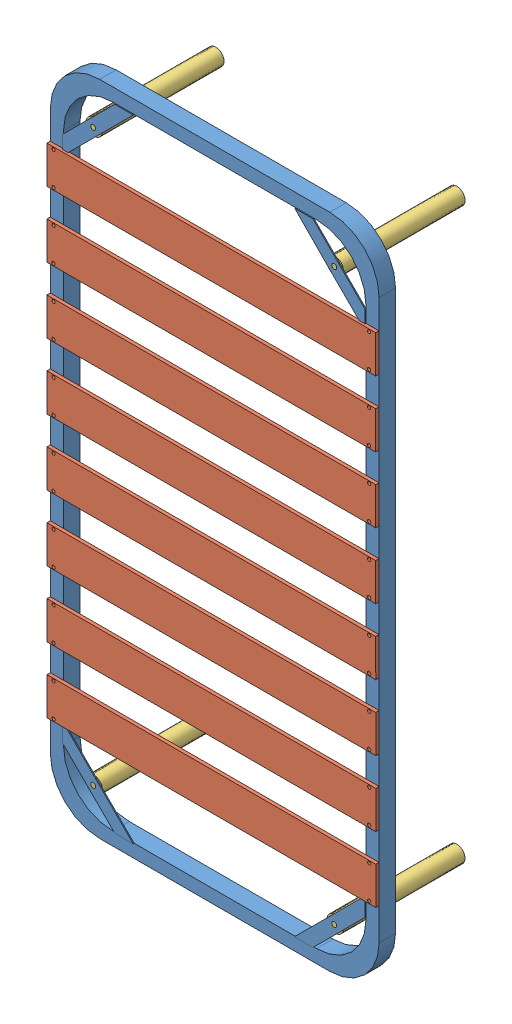
SolidWorks assembly rete completa, configuration Default. Lengths in mm.
Overall size (1000.42 2000 380).
13 component instances, 3 part files, 32 mates.
Components (placement in the parent):
- rete-1: rete [Default] at (-585.6173 107.8068 1973.5) size (1000 2000 53)
- doga-1: doga [Default] at (-585.6313 -587.1802 2023.5) x (1 0.00028 0) z (0 0 1) size (1000 114 10)
- doga-2: doga [Default] at (-585.6872 -387.1802 2023.5) x (1 0.00028 0) z (0 0 1) size (1000 114 10)
- doga-3: doga [Default] at (-585.7431 -187.1802 2023.5) x (1 0.00028 0) z (0 0 1) size (1000 114 10)
- doga-4: doga [Default] at (-585.799 12.8198 2023.5) x (1 0.00028 0) z (0 0 1) size (1000 114 10)
- doga-5: doga [Default] at (-585.855 212.8198 2023.5) x (1 0.00028 0) z (0 0 1) size (1000 114 10)
- doga-6: doga [Default] at (-585.9668 612.8197 2023.5) x (1 0.00028 0) z (0 0 1) size (1000 114 10)
- doga-7: doga [Default] at (-585.9109 412.8198 2023.5) x (1 0.00028 0) z (0 0 1) size (1000 114 10)
- doga-8: doga [Default] at (-586.0227 812.8197 2023.5) x (1 0.00028 0) z (0 0 1) size (1000 114 10)
- piede rete-1: piede rete [Default] at (-219.0488 -758.7617 1653.5) x (0.410103 0.912039 0) z (0 0 1) size (50 50 373)
- piede rete-2: piede rete [Default] at (-952.1859 -758.7617 1653.5) size (50 50 373)
- piede rete-3: piede rete [Default] at (-952.1859 974.3754 1653.5) size (50 50 373)
- piede rete-4: piede rete [Default] at (-219.0529 974.3804 1653.5) size (50 50 373)
Mates (geometry in assembly coordinates):
- Concentrico1: concentric aligned: circle of rete-1; circle of doga-1
- Concentrico2: concentric aligned: circle of rete-1; circle of doga-1
- Coincidente1: coincident anti-aligned: plane of rete-1 through (-585.6173 107.8068 2023.5) normal (0 0 1); plane of doga-1 through (-585.6313 -587.1802 2023.5) normal (0 0 -1)
- Concentrico3: concentric aligned: circle of rete-1; circle of doga-2
- Concentrico4: concentric aligned: circle of rete-1; circle of doga-2
- Coincidente2: coincident anti-aligned: plane of rete-1 through (-585.6173 107.8068 2023.5) normal (0 0 1); plane of doga-2 through (-585.6872 -387.1802 2023.5) normal (0 0 -1)
- Concentrico5: concentric aligned: circle of rete-1; circle of doga-3
- Concentrico6: concentric aligned: circle of rete-1; circle of doga-3
- Coincidente3: coincident anti-aligned: plane of rete-1 through (-585.6173 107.8068 2023.5) normal (0 0 1); plane of doga-3 through (-585.7431 -187.1802 2023.5) normal (0 0 -1)
- Concentrico7: concentric aligned: circle of rete-1; circle of doga-4
- Concentrico8: concentric aligned: circle of rete-1; circle of doga-4
- Coincidente4: coincident anti-aligned: plane of rete-1 through (-585.6173 107.8068 2023.5) normal (0 0 1); plane of doga-4 through (-585.799 12.8198 2023.5) normal (0 0 -1)
- Concentrico9: concentric aligned: circle of rete-1; circle of doga-5
- Concentrico10: concentric aligned: circle of rete-1; circle of doga-5
- Coincidente5: coincident anti-aligned: plane of rete-1 through (-585.6173 107.8068 2023.5) normal (0 0 1); plane of doga-5 through (-585.855 212.8198 2023.5) normal (0 0 -1)
- Concentrico11: concentric aligned: circle of rete-1; circle of doga-7
- Concentrico12: concentric aligned: circle of rete-1; circle of doga-7
- Coincidente6: coincident anti-aligned: plane of rete-1 through (-585.6173 107.8068 2023.5) normal (0 0 1); plane of doga-7 through (-585.9109 412.8198 2023.5) normal (0 0 -1)
- Concentrico13: concentric aligned: circle of rete-1; circle of doga-6
- Concentrico14: concentric aligned: circle of rete-1; circle of doga-6
- Coincidente7: coincident anti-aligned: plane of rete-1 through (-585.6173 107.8068 2023.5) normal (0 0 1); plane of doga-6 through (-585.9668 612.8197 2023.5) normal (0 0 -1)
- Concentrico15: concentric aligned: circle of rete-1; circle of doga-8
- Concentrico16: concentric aligned: circle of rete-1; circle of doga-8
- Coincidente8: coincident anti-aligned: plane of rete-1 through (-585.6173 107.8068 2023.5) normal (0 0 1); plane of doga-8 through (-586.0227 812.8197 2023.5) normal (0 0 -1)
- Concentrico17: concentric anti-aligned: cylinder of rete-1 through (-219.0488 -758.7617 1973.5) axis (0 0 1) radius 7.5; cylinder of piede rete-1 through (-219.0488 -758.7617 2026.5) axis (0 0 -1) radius 7.5
- Coincidente9: coincident aligned: plane of rete-1 through (-585.6173 107.8068 2026.5) normal (0 0 1); plane of piede rete-1 through (-219.0488 -758.7617 2026.5) normal (0 0 1)
- Coincidente10: coincident aligned: plane of rete-1 through (-585.6173 107.8068 2026.5) normal (0 0 1); plane of piede rete-2 through (-952.1859 -758.7617 2026.5) normal (0 0 1)
- Concentrico18: concentric anti-aligned: cylinder of rete-1 through (-952.1859 -758.7617 1973.5) axis (0 0 1) radius 7.5; cylinder of piede rete-2 through (-952.1859 -758.7617 2026.5) axis (0 0 -1) radius 7.5
- Concentrico19: concentric anti-aligned: cylinder of rete-1 through (-952.1859 974.3754 1973.5) axis (0 0 1) radius 7.5; cylinder of piede rete-3 through (-952.1859 974.3754 2026.5) axis (0 0 -1) radius 7.5
- Coincidente11: coincident aligned: plane of rete-1 through (-585.6173 107.8068 2026.5) normal (0 0 1); plane of piede rete-3 through (-952.1859 974.3754 2026.5) normal (0 0 1)
- Concentrico20: concentric anti-aligned: cylinder of rete-1 through (-219.0529 974.3804 1973.5) axis (0 0 1) radius 7.5; cylinder of piede rete-4 through (-219.0529 974.3804 2026.5) axis (0 0 -1) radius 7.5
- Coincidente12: coincident aligned: plane of rete-1 through (-585.6173 107.8068 2026.5) normal (0 0 1); plane of piede rete-4 through (-219.0529 974.3804 2026.5) normal (0 0 1)
